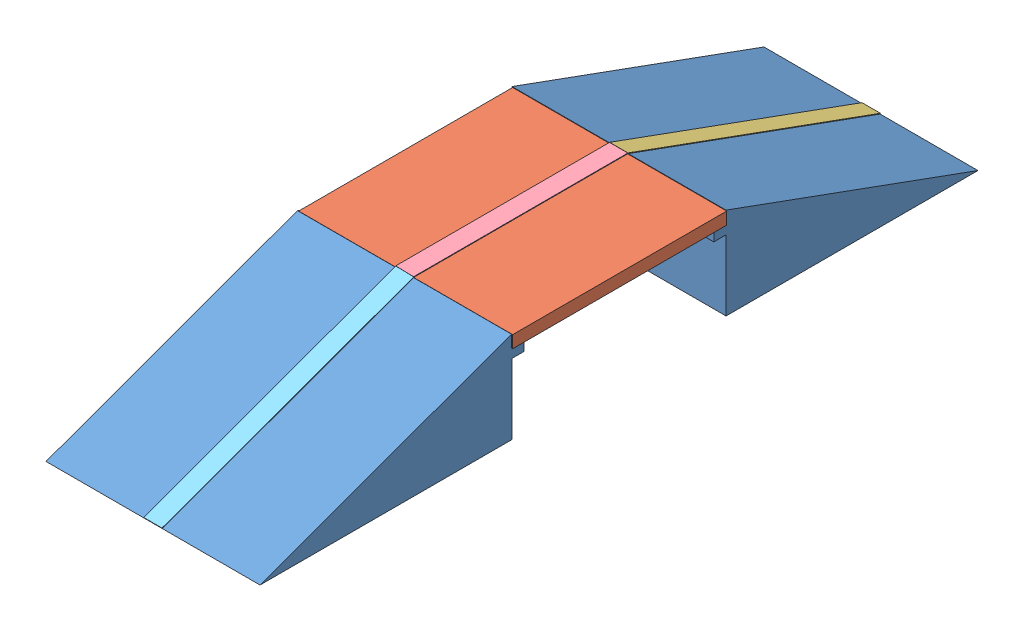
SolidWorks assembly Bridge, configuration Default. Lengths in mm.
Overall size (351.87 151.15 1174.68).
6 component instances, 5 part files, 16 mates.
Components (placement in the parent):
- Ramp-1: Ramp [Default] at (248.3625 187.8226 568.5948) size (350 149.96 432)
- square-1: square [Default] at (140.0704 317.7783 0.318) x (0 0 1) z (-1 0 0) size (350 20 350)
- Ramp-2: Ramp [Default] at (-101.6375 187.8226 -605.4052) x (-1 0 0) z (0 0 -1) size (350 149.96 432)
- Part2^Bridge-1: Part2^Bridge [Default] at (-101.6375 187.8226 -605.4052) x (-1 0 0) z (0 0.939693 -0.34202) size (30 439.19 1) (virtual)
- Part3^Bridge-1: Part3^Bridge [Default] at (140.0704 337.7783 0.318) x (0 0 1) z (0 1 0) size (350.8 30 1) (virtual)
- Part4^Bridge-1: Part4^Bridge [Default] at (248.3625 187.8226 568.5948) x (1 0 0) z (0 0.939693 0.34202) size (30 438.44 1) (virtual)
Mates (geometry in assembly coordinates):
- Distance1: distance = 350 mm anti-aligned: plane of Ramp-2 through (248.3625 187.8226 -193.4052) normal (0 0 1); plane of Ramp-1 through (-101.6375 187.8226 156.5948) normal (0 0 -1)
- Coincident4: coincident aligned: plane of Ramp-1 through (-101.6375 187.8226 568.5948) normal (0 -1 0); plane of Ramp-2 through (248.3625 187.8226 -605.4052) normal (0 -1 0)
- Coincident5: coincident aligned: plane of Ramp-1 through (-101.6375 187.8226 568.5948) normal (-1 0 0); plane of Ramp-2 through (-101.6375 187.8226 -605.4052) normal (-1 0 0)
- Coincident8: coincident anti-aligned: plane of Ramp-1 through (248.3625 317.7783 136.5948) normal (0 1 0); plane of square-1 through (140.0704 317.7783 0.318) normal (0 -1 0)
- InPlace1: in place: plane of Ramp-2 through (248.3625 337.7783 -193.4052) normal (0 0.939693 -0.34202); plane of ? through (0 360.425 -131.184) normal (0 0.939693 -0.34202); moOrthogonalPlaneRef_w of Ramp-2 through (248.3625 337.7783 -193.4052) normal (0 0.939693 -0.34202); plane of ? through (0 360.425 -131.184) normal (0 -0.34202 -0.939693); plane of Ramp-2 through (248.3625 337.7783 -193.4052) normal (0 0.939693 -0.34202); plane of ? through (0 360.425 -131.184) normal (1 0 0); plane of Ramp-2 through (248.3625 337.7783 -193.4052) normal (0 0.939693 -0.34202); unknown of Part2^Bridge-1
- Coincident9: coincident aligned: plane of Ramp-2; plane of Part2^Bridge-1
- Coincident10: coincident aligned: moOrthogonalPlaneRef_w of Ramp-2 through (-101.6375 187.8226 -605.4052) normal (0 0.34202 0.939693); plane of Part2^Bridge-1 through (-101.6375 187.8226 -605.4052) normal (0 0.34202 0.939693)
- Coincident11: coincident anti-aligned: moOrthogonalPlaneRef_w of Ramp-2 through (-101.6375 187.8226 -605.4052) normal (1 0 0); plane of Part2^Bridge-1 through (-101.6375 187.8226 -605.4052) normal (-1 0 0)
- InPlace2: in place: plane of square-1 through (140.0704 337.7783 0.318) normal (0 1 0); plane of ? through (0 337.7783 0) normal (0 1 0); plane of square-1 through (140.0704 337.7783 0.318) normal (0 1 0); plane of ? through (0 337.7783 0) normal (0 0 -1); plane of square-1 through (140.0704 337.7783 0.318) normal (0 1 0); plane of ? through (0 337.7783 0) normal (1 0 0); plane of square-1 through (140.0704 337.7783 0.318) normal (0 1 0); unknown of Part3^Bridge-1
- Coincident12: coincident aligned: plane of square-1; plane of Part3^Bridge-1
- Coincident13: coincident aligned: moOrthogonalPlaneRef_w of square-1 through (140.0704 337.7783 0.318) normal (1 0 0); plane of Part3^Bridge-1 through (140.0704 337.7783 0.318) normal (1 0 0)
- Coincident14: coincident anti-aligned: moOrthogonalPlaneRef_w of square-1 through (140.0704 337.7783 0.318) normal (0 0 -1); plane of Part3^Bridge-1 through (140.0704 337.7783 0.318) normal (0 0 1)
- InPlace3: in place: plane of Ramp-1 through (-101.6375 337.7783 156.5948) normal (0 0.939693 0.34202); plane of ? through (0 348.5944 126.878) normal (0 0.939693 0.34202); plane of Ramp-1 through (-101.6375 337.7783 156.5948) normal (0 0.939693 0.34202); plane of ? through (0 348.5944 126.878) normal (0 0.34202 -0.939693); plane of Ramp-1 through (-101.6375 337.7783 156.5948) normal (0 0.939693 0.34202); plane of ? through (0 348.5944 126.878) normal (1 0 0); plane of Ramp-1 through (-101.6375 337.7783 156.5948) normal (0 0.939693 0.34202); unknown of Part4^Bridge-1
- Coincident15: coincident aligned: plane of Ramp-1; plane of Part4^Bridge-1
- Coincident16: coincident aligned: moOrthogonalPlaneRef_w of Ramp-1 through (248.3625 187.8226 568.5948) normal (0 0.34202 -0.939693); plane of Part4^Bridge-1 through (248.3625 187.8226 568.5948) normal (0 0.34202 -0.939693)
- Coincident17: coincident anti-aligned: moOrthogonalPlaneRef_w of Ramp-1 through (248.3625 187.8226 568.5948) normal (-1 0 0); plane of Part4^Bridge-1 through (248.3625 187.8226 568.5948) normal (1 0 0)
